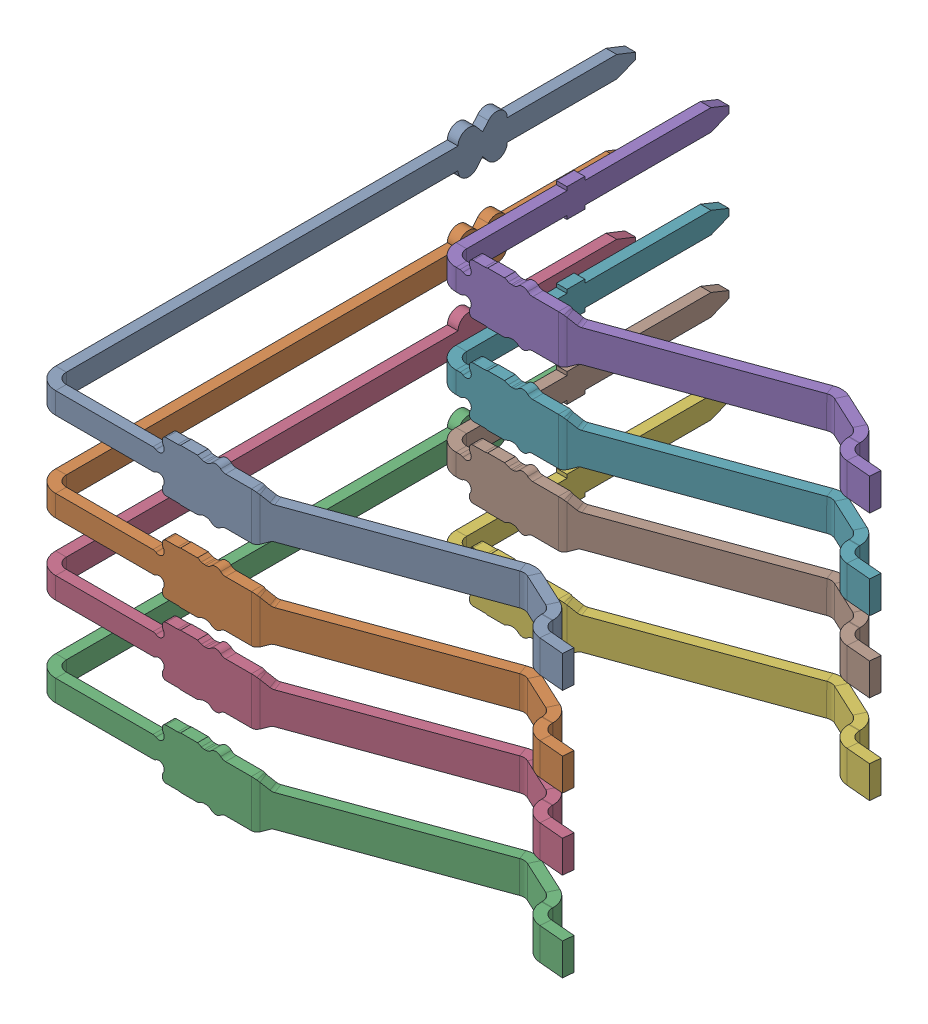
SolidWorks assembly leads_1.stp, configuration Default. Lengths in mm.
Overall size (14.29 8.54 16.6).
8 component instances, 2 part files, 0 mates.
Components (placement in the parent):
- top_lead.stp-1: top_lead.stp [Default] at origin size (14.29 1.54 16.6)
- top_lead.stp-2: top_lead.stp [Default] at (0 -2.5 0) size (14.29 1.54 16.6)
- top_lead.stp-3: top_lead.stp [Default] at (0 -7 0) size (14.29 1.54 16.6)
- top_lead.stp-4: top_lead.stp [Default] at (0 -4.5 0) size (14.29 1.54 16.6)
- bottom_lead.stp-1: bottom_lead.stp [Default] at origin size (11.67 1.54 7.97)
- bottom_lead.stp-2: bottom_lead.stp [Default] at (0 -7 0) size (11.67 1.54 7.97)
- bottom_lead.stp-3: bottom_lead.stp [Default] at (0 -2.5 0) size (11.67 1.54 7.97)
- bottom_lead.stp-4: bottom_lead.stp [Default] at (0 -4.5 0) size (11.67 1.54 7.97)
